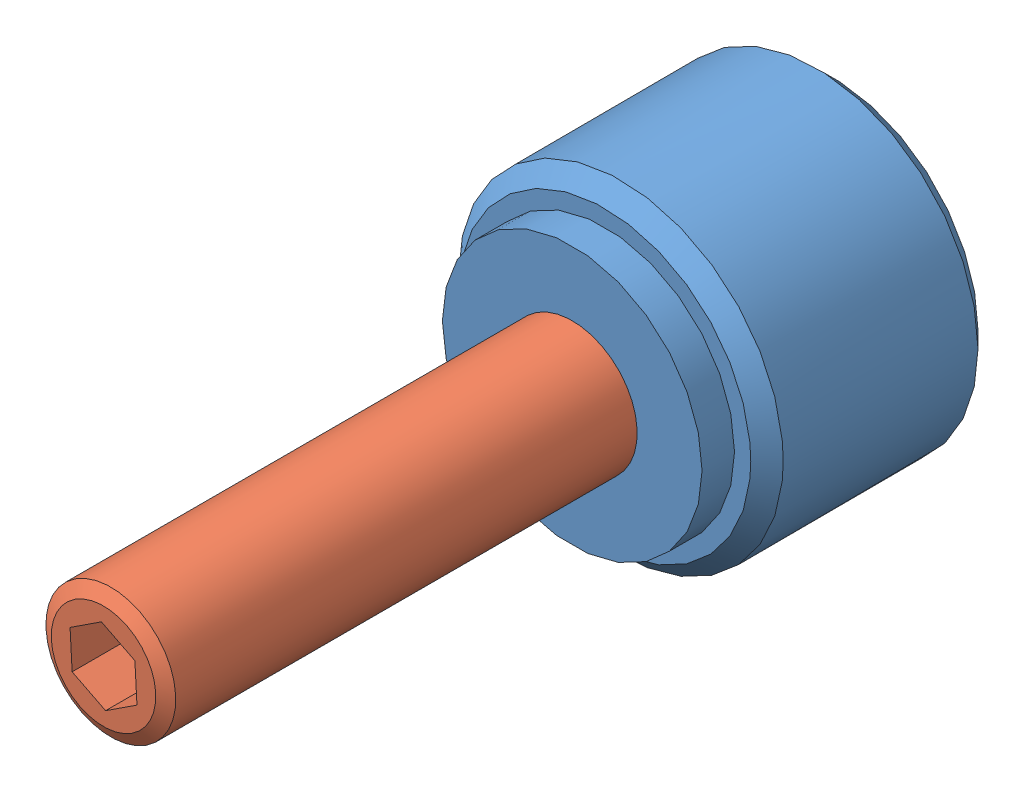
SolidWorks assembly thumbscrew_screw, configuration По умолчанию. Lengths in mm.
Overall size (10 10 22.44).
2 component instances, 2 part files, 1 mates.
Components (placement in the parent):
- thumbscrew-1: thumbscrew [По умолчанию] at (-18.0221 -2.9045 15.4261) size (10 10 8)
- socket set screw cone point_din-2: socket set screw cone point_din [DIN 914 - M4 x 20-C] at (-18.0221 -2.9045 37.8654) x (0 0 -1) z (0.892379 -0.451286 0) size (20 4 4)
Mates (geometry in assembly coordinates):
- Концентричный1: concentric aligned: cylinder of thumbscrew-1 through (-18.0221 -2.9045 23.4261) axis (0 0 1) radius 1.65; cylinder of socket set screw cone point_din-2 through (-18.0221 -2.9045 50.5654) axis (0 0 1) radius 2
